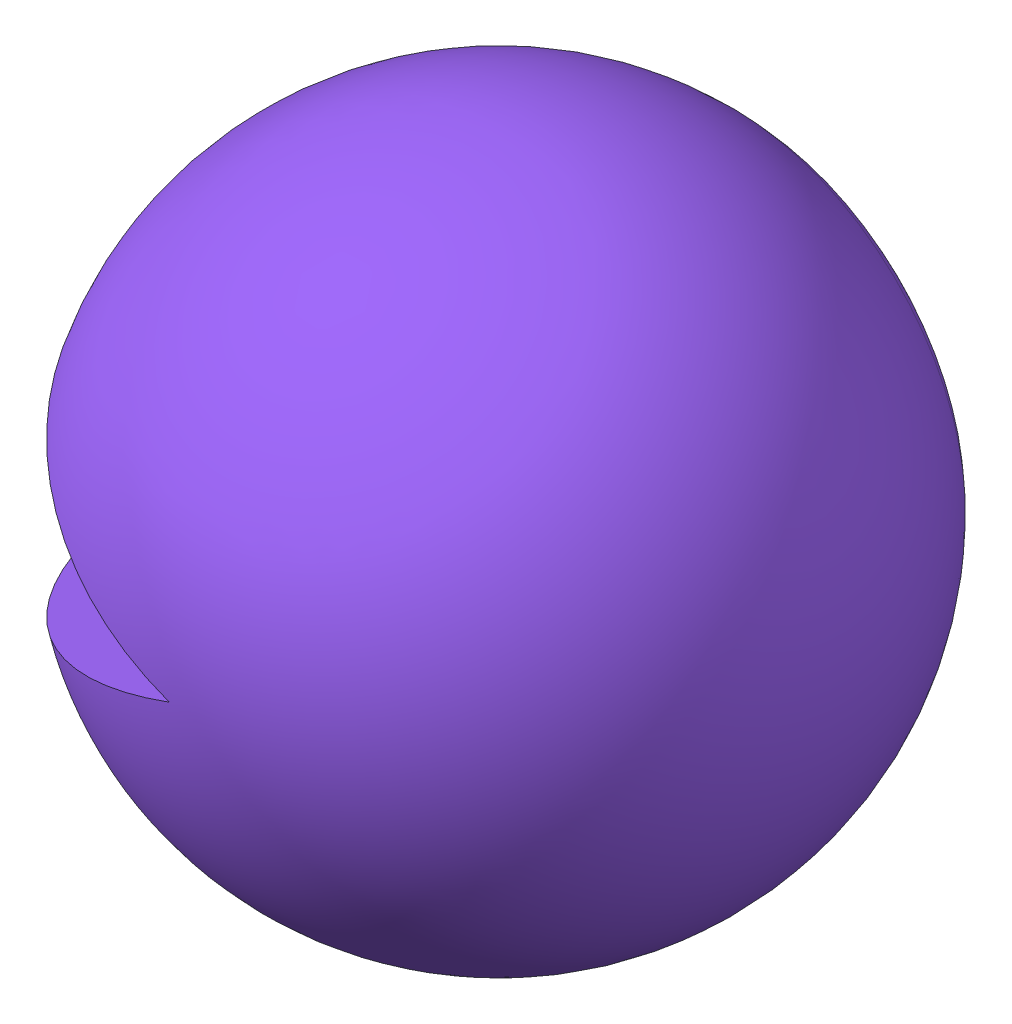
SolidWorks assembly GR6150-2000 机器人数模（L侧）-2016 V1.0, configuration 默认. Lengths in mm.
Overall size (5211.44 5211.44 3773.11).
8 component instances, 8 part files, 27 mates.
Components (placement in the parent):
- 复件 底座^GR6150-2000 机器人数模（L侧）-2016 V1.0-3: 复件 底座^GR6150-2000 机器人数模（L侧）-2016 V1.0 [默认] at (-75.5764 34.0027 647.3326) x (-1 0 0) z (0 1 0) size (675 510 660) (virtual)
- 复件 转座^GR6150-2000 机器人数模（L侧）-2016 V1.0-2: 复件 转座^GR6150-2000 机器人数模（L侧）-2016 V1.0 [默认] at (-65.5435 35.1938 562.2241) x (-1 0 0) z (0 1 0) size (545.36 673.77 602.58) (virtual)
- 复件 大臂^GR6150-2000 机器人数模（L侧）-2016 V1.0-1: 复件 大臂^GR6150-2000 机器人数模（L侧）-2016 V1.0 [默认] at (-65.5435 35.1938 562.2241) x (-1 0 0) z (0 1 0) size (480 1380 306.5) (virtual)
- 复件 工艺臂^GR6150-2000 机器人数模（L侧）-2016 V1.0-4: 复件 工艺臂^GR6150-2000 机器人数模（L侧）-2016 V1.0 [默认] at (131.4749 35.1938 201.3339) x (-0.979925 0 0.199368) z (0 1 0) size (1291.88 538.61 459.55) (virtual)
- 复件 J4^GR6150-2000 机器人数模（L侧）-2016 V1.0-1: 复件 J4^GR6150-2000 机器人数模（L侧）-2016 V1.0 [默认] at (-338.5251 35.1938 201.334) x (-0.979925 0 0.199368) z (0 1 0) size (212.05 184.72 176) (virtual)
- 复件 J5^GR6150-2000 机器人数模（L侧）-2016 V1.0-1: 复件 J5^GR6150-2000 机器人数模（L侧）-2016 V1.0 [默认] at (-338.5251 35.1933 201.3339) x (-0.979925 0 0.199368) z (0 1 0) size (162.94 140.06 134.71) (virtual)
- 复件 法兰^GR6150-2000 机器人数模（L侧）-2016 V1.0-2: 复件 法兰^GR6150-2000 机器人数模（L侧）-2016 V1.0 [默认] at (1162.1092 0 1698.0434) x (-1 0 0) z (0 1 0) size (32 114.86 115) (virtual)
- 复件 运动范围图^GR6150-2000 机器人数模（L侧）-2016 V1.0-2: 复件 运动范围图^GR6150-2000 机器人数模（L侧）-2016 V1.0 [默认] at (0 0 800) x (0.939693 0.34202 0) z (0.34202 -0.939693 0) size (4066 3773.11 4066) (virtual)
Mates (geometry in assembly coordinates):
- 重合1: coincident anti-aligned: plane of 复件 底座^GR6150-2000 机器人数模（L侧）-2016 V1.0-3 through (-325 -244.5108 0) normal (0 0 -1); plane of assembly through (0 0 0) normal (0 0 1)
- 距离1: distance = 330 mm anti-aligned: plane of 复件 底座^GR6150-2000 机器人数模（L侧）-2016 V1.0-3 through (-450 -330 0) normal (0 -1 0); plane of assembly through (0 0 0) normal (0 1 0)
- 距离2: distance = 450 mm anti-aligned: plane of 复件 底座^GR6150-2000 机器人数模（L侧）-2016 V1.0-3 through (-450 -250 0) normal (-1 0 0); plane of assembly through (0 0 0) normal (1 0 0)
- 同心1: concentric anti-aligned: cylinder of 复件 转座^GR6150-2000 机器人数模（L侧）-2016 V1.0-2 through (0 0 475) axis (0 0 -1) radius 225; cone of 复件 底座^GR6150-2000 机器人数模（L侧）-2016 V1.0-3 through (0 0 420.6757) axis (0 0 1)
- 距离3: distance = 64.5 mm anti-aligned: plane of 复件 底座^GR6150-2000 机器人数模（L侧）-2016 V1.0-3 through (296.9703 122.602 390.5) normal (0 0 1); plane of 复件 转座^GR6150-2000 机器人数模（L侧）-2016 V1.0-2 through (255 -180 455) normal (0 0 -1)
- LimitAngle1: limit planar angle = 0 rad aligned: plane of 复件 转座^GR6150-2000 机器人数模（L侧）-2016 V1.0-2 through (-4 -217.5 425) normal (1 0 0); plane of 复件 底座^GR6150-2000 机器人数模（L侧）-2016 V1.0-3 through (-4 -224.9644 415.5) normal (1 0 0)
- 转座回归初始位置: parallel aligned: plane of 复件 转座^GR6150-2000 机器人数模（L侧）-2016 V1.0-2 through (4 -217.5 410) normal (-1 0 0); plane of 复件 底座^GR6150-2000 机器人数模（L侧）-2016 V1.0-3 through (4 -228.5 415.5) normal (-1 0 0)
- 同心2: concentric anti-aligned: cylinder of 复件 转座^GR6150-2000 机器人数模（L侧）-2016 V1.0-2 through (0 90.1642 800) axis (0 -1 0) radius 255; cylinder of 复件 大臂^GR6150-2000 机器人数模（L侧）-2016 V1.0-1 through (0 -185 800) axis (0 1 0) radius 224.75
- 距离4: distance = 5 mm anti-aligned: plane of 复件 大臂^GR6150-2000 机器人数模（L侧）-2016 V1.0-1 through (242.88 -185 557.12) normal (0 1 0); plane of 复件 转座^GR6150-2000 机器人数模（L侧）-2016 V1.0-2 through (-255 -180 455) normal (0 -1 0)
- LimitAngle2: limit planar angle = 0 rad aligned: plane of 复件 大臂^GR6150-2000 机器人数模（L侧）-2016 V1.0-1 through (4 -195.6 1079.8817) normal (-1 0 0); plane of 复件 转座^GR6150-2000 机器人数模（L侧）-2016 V1.0-2 through (4 -171.85 1067.7716) normal (-1 0 0)
- 大臂回归初始位置: parallel aligned: plane of 复件 转座^GR6150-2000 机器人数模（L侧）-2016 V1.0-2 through (-4 -156.85 1067.7716) normal (1 0 0); plane of 复件 大臂^GR6150-2000 机器人数模（L侧）-2016 V1.0-1 through (-4 -195.6 1067.8817) normal (1 0 0)
- 同心3: concentric aligned: cylinder of 复件 大臂^GR6150-2000 机器人数模（L侧）-2016 V1.0-1 through (0 -379.6 1800) axis (0 1 0) radius 140; cylinder of 复件 工艺臂^GR6150-2000 机器人数模（L侧）-2016 V1.0-4 through (0 -210 1800) axis (0 1 0) radius 140
- 距离5: distance = 4.6 mm anti-aligned: plane of 复件 工艺臂^GR6150-2000 机器人数模（L侧）-2016 V1.0-4 through (141.68 -210 1941.68) normal (0 -1 0); plane of 复件 大臂^GR6150-2000 机器人数模（L侧）-2016 V1.0-1 through (-138.9198 -214.6 1658.32) normal (0 1 0)
- LimitAngle3: limit planar angle = 0 rad aligned: plane of 复件 大臂^GR6150-2000 机器人数模（L侧）-2016 V1.0-1 through (159.3742 -218.1 1802) normal (0 0 -1); plane of 复件 工艺臂^GR6150-2000 机器人数模（L侧）-2016 V1.0-4 through (159.95 -209 1804) normal (0 0 -1)
- 工艺臂回归初始位置: parallel aligned: plane of 复件 大臂^GR6150-2000 机器人数模（L侧）-2016 V1.0-1 through (159.3742 -233.1 1794) normal (0 0 1); plane of 复件 工艺臂^GR6150-2000 机器人数模（L侧）-2016 V1.0-4 through (170 -209 1796) normal (0 0 1)
- 同心4: concentric anti-aligned: cylinder of 复件 J4^GR6150-2000 机器人数模（L侧）-2016 V1.0-1 through (987.4865 0 1800) axis (1 0 0) radius 80; cylinder of 复件 工艺臂^GR6150-2000 机器人数模（L侧）-2016 V1.0-4 through (945 0 1800) axis (-1 0 0) radius 104
- 距离8: distance = 7 mm anti-aligned: plane of 复件 工艺臂^GR6150-2000 机器人数模（L侧）-2016 V1.0-4 through (963 74.4216 1671.0981) normal (1 0 0); plane of 复件 J4^GR6150-2000 机器人数模（L侧）-2016 V1.0-1 through (970 0 1883.5) normal (-1 0 0)
- J4回归初始位置: concentric anti-aligned: cylinder of 复件 J4^GR6150-2000 机器人数模（L侧）-2016 V1.0-1 through (985 0 1895) axis (-1 0 0) radius 4; cylinder of 复件 工艺臂^GR6150-2000 机器人数模（L侧）-2016 V1.0-4 through (960 0 1895) axis (1 0 0) radius 4
- 同心6: concentric aligned: cylinder of 复件 J4^GR6150-2000 机器人数模（L侧）-2016 V1.0-1 through (1057.4544 0 1732.812) axis (0.34202 0 -0.939693) radius 77; cylinder of 复件 J5^GR6150-2000 机器人数模（L侧）-2016 V1.0-1 through (1070.1092 0 1698.0434) axis (0.34202 0 -0.939693) radius 60
- 距离6: distance = 10 mm anti-aligned: plane of 复件 J5^GR6150-2000 机器人数模（L侧）-2016 V1.0-1 through (1086.9235 0 1754.1796) normal (-0.34202 0 0.939693); plane of 复件 J4^GR6150-2000 机器人数模（L侧）-2016 V1.0-1 through (1057.4544 77 1732.812) normal (0.34202 0 -0.939693)
- J5回归初始位置: parallel aligned: plane of 复件 J4^GR6150-2000 机器人数模（L侧）-2016 V1.0-1 through (985 0 1886) normal (1 0 0); plane of 复件 J5^GR6150-2000 机器人数模（L侧）-2016 V1.0-1 through (1145.1092 0 1760.0434) normal (1 0 0)
- 同心7: concentric aligned: cylinder of 复件 J5^GR6150-2000 机器人数模（L侧）-2016 V1.0-1 through (1145.1092 0 1698.0434) axis (1 0 0) radius 62; cylinder of 复件 法兰^GR6150-2000 机器人数模（L侧）-2016 V1.0-2 through (1154.1092 0 1698.0434) axis (1 0 0) radius 46
- 距离7: distance = 1 mm anti-aligned: plane of 复件 法兰^GR6150-2000 机器人数模（L侧）-2016 V1.0-2 through (1146.1092 -58.19 1639.8542) normal (-1 0 0); plane of 复件 J5^GR6150-2000 机器人数模（L侧）-2016 V1.0-1 through (1145.1092 0 1760.0434) normal (1 0 0)
- 法兰回归初始位置: concentric aligned: cylinder of 复件 J5^GR6150-2000 机器人数模（L侧）-2016 V1.0-1 through (1143.1092 0 1755.0434) axis (1 0 0) radius 4; cylinder of 复件 法兰^GR6150-2000 机器人数模（L侧）-2016 V1.0-2 through (1146.1092 0 1755.0434) axis (1 0 0) radius 4
- 同心9: concentric: sphere of 复件 运动范围图^GR6150-2000 机器人数模（L侧）-2016 V1.0-2; cylinder of 复件 底座^GR6150-2000 机器人数模（L侧）-2016 V1.0-3 through (0 0 351.5) axis (0 0 1) radius 224.75
- 重合3: coincident anti-aligned: plane of 复件 底座^GR6150-2000 机器人数模（L侧）-2016 V1.0-3 through (-325 -244.5108 0) normal (0 0 -1); plane of 复件 运动范围图^GR6150-2000 机器人数模（L侧）-2016 V1.0-2 through (0 0 0) normal (0 0 1)
- 平行5: parallel anti-aligned: plane of 复件 运动范围图^GR6150-2000 机器人数模（L侧）-2016 V1.0-2; plane of 复件 底座^GR6150-2000 机器人数模（L侧）-2016 V1.0-3 through (-75.5764 34.0027 647.3326) normal (0 1 0)
